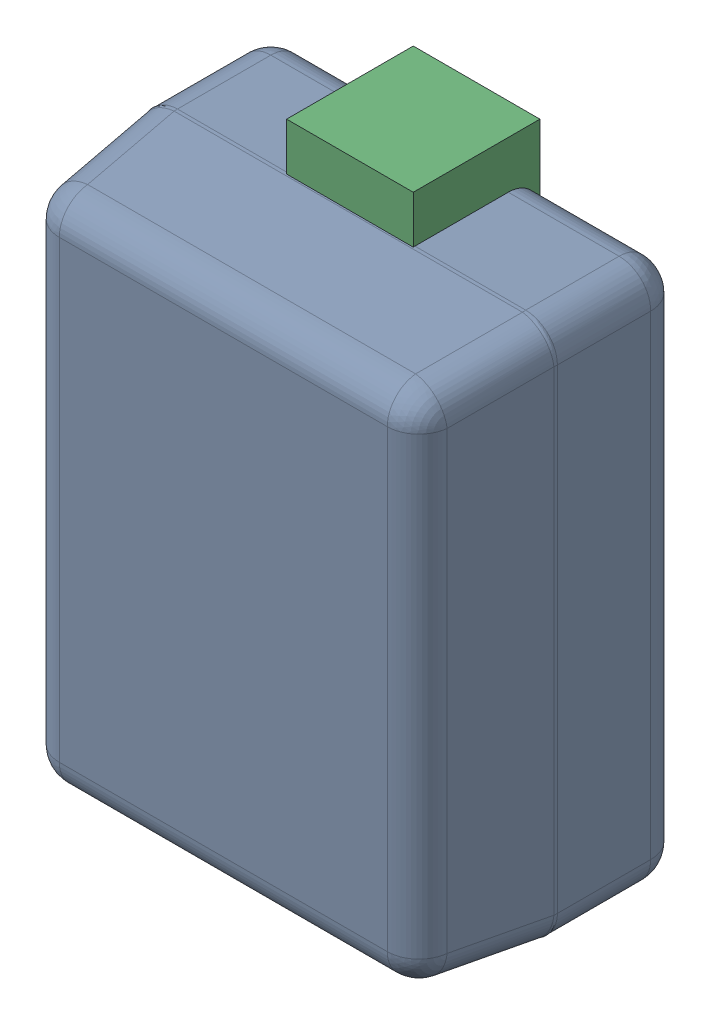
SolidWorks assembly D80.step, configuration Default. Lengths in mm.
Overall size (0.66 1 0.4).
5 component instances, 2 part files, 0 mates.
Components (placement in the parent):
- 6297722768.step-1: 6297722768.step [Default] at (23.7998 -1.9844 0) x (0 1 0) z (0 0 1) size (1 0.66 0.4)
  - Body (8).step-1: Body (8).step [Default] at (-0.425 -0.325 0) size (0.85 0.66 0.4)
    - Open CASCADE STEP translator 6.8 15.1.1.step-1: Open CASCADE STEP translator 6.8 15.1.1.step [Default] at origin size (0.85 0.66 0.4)
  - lead.step-1: lead.step [Default] at (-0.5 -0.1 0) size (0.19 0.2 0.2)
  - lead.step-2: lead.step [Default] at (0.5 0.1 0) x (-1 0 0) z (0 0 1) size (0.19 0.2 0.2)
